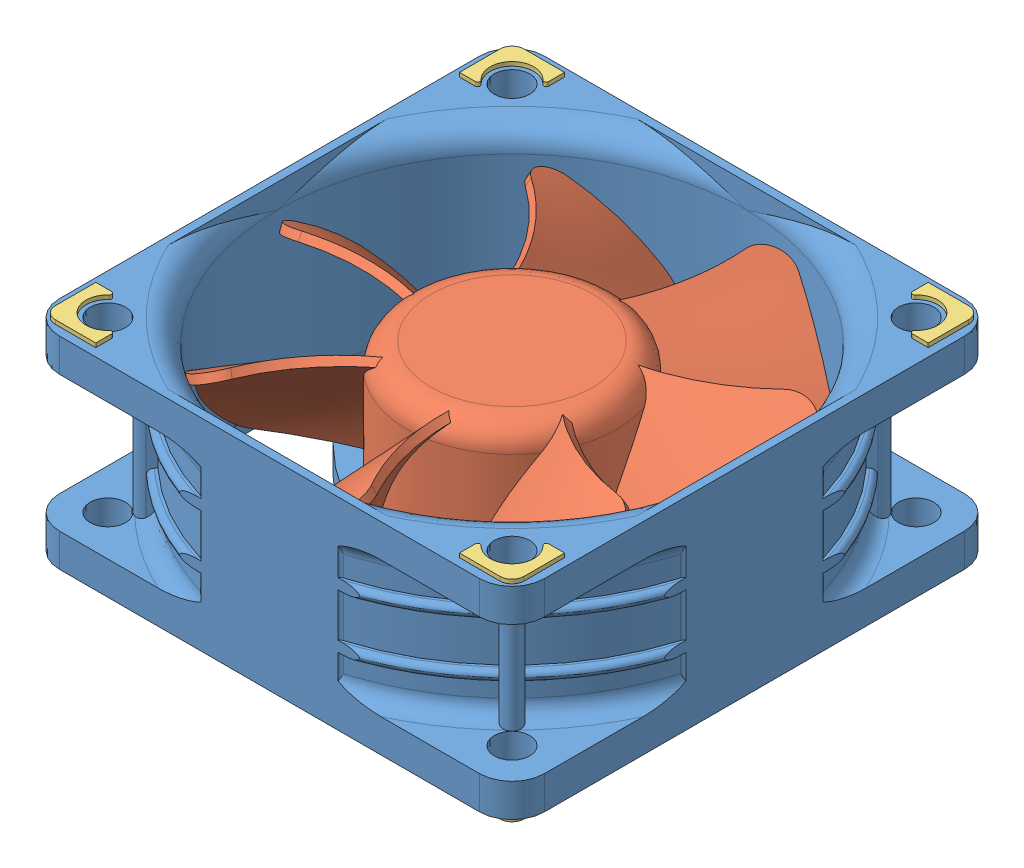
SolidWorks assembly NF A6x25.step, configuration Default. Lengths in mm.
Overall size (64.02 26 64.02).
3 component instances, 3 part files, 0 mates.
Components (placement in the parent):
- Component1.step-1: Component1.step [Default] at (0 13 0) x (1 0 0) z (0 0 -1) size (64.02 25.02 64.02)
- Component2.step-1: Component2.step [Default] at (0 11 0.7708) x (1 0 0) z (0 0 -1) size (59.47 16.42 59.01)
- Component3.step-1: Component3.step [Default] at (0 13 0) x (1 0 0) z (0 0 -1) size (58 26 58)
